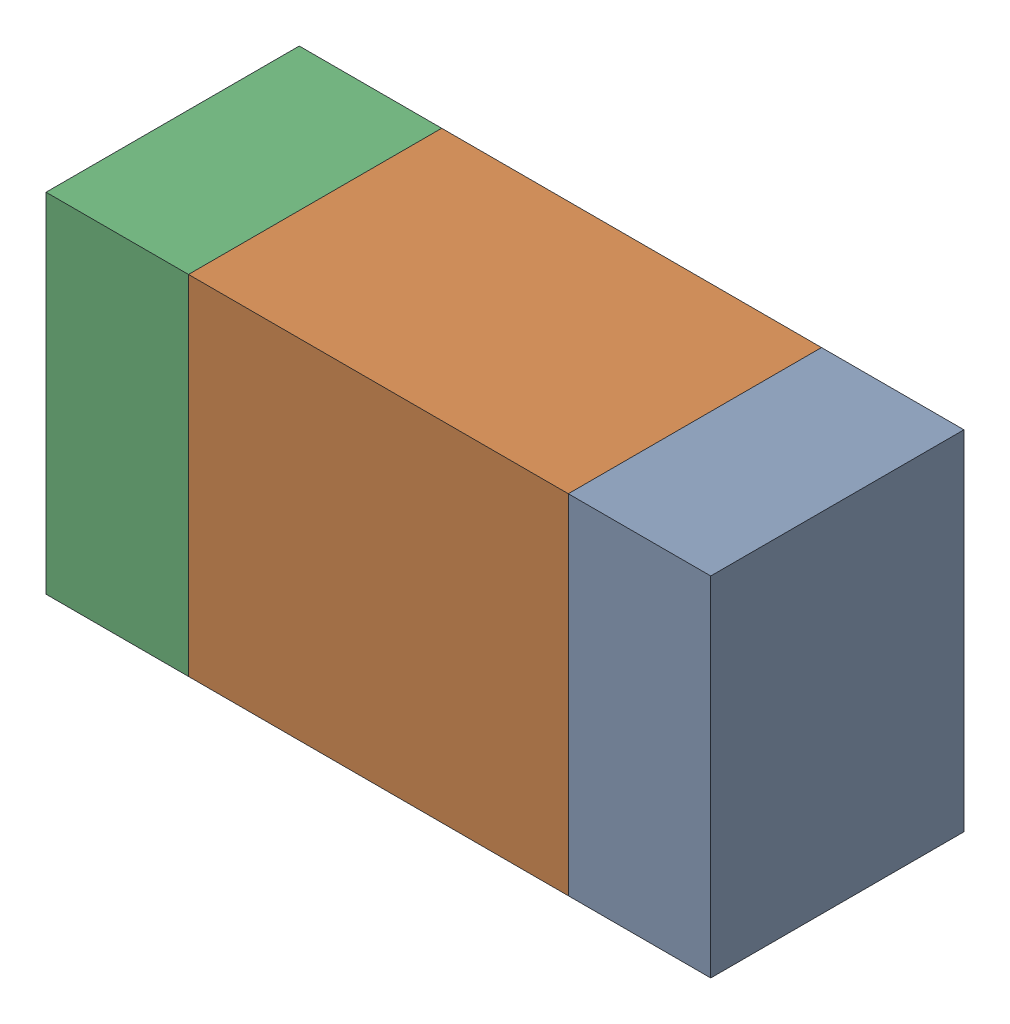
SolidWorks assembly R201PCB, configuration Default. Lengths in mm.
Overall size (1.05 0.55 0.4).
6 component instances, 2 part files, 0 mates.
Components (placement in the parent):
- 854785432-1: 854785432 [Default] at (95.1126 122.5001 0) size (0.22 0.55 0.4)
  - Extruded-1: Extruded [Default] at origin size (0.22 0.55 0.4)
- 854785568-1: 854785568 [Default] at (94.7001 122.5001 0) size (0.6 0.55 0.4)
  - Extruded_2-1: Extruded_2 [Default] at origin size (0.6 0.55 0.4)
- 854785432-2: 854785432 [Default] at (94.2876 122.5001 0) size (0.22 0.55 0.4)
  - Extruded-1: Extruded [Default] at origin size (0.22 0.55 0.4)
